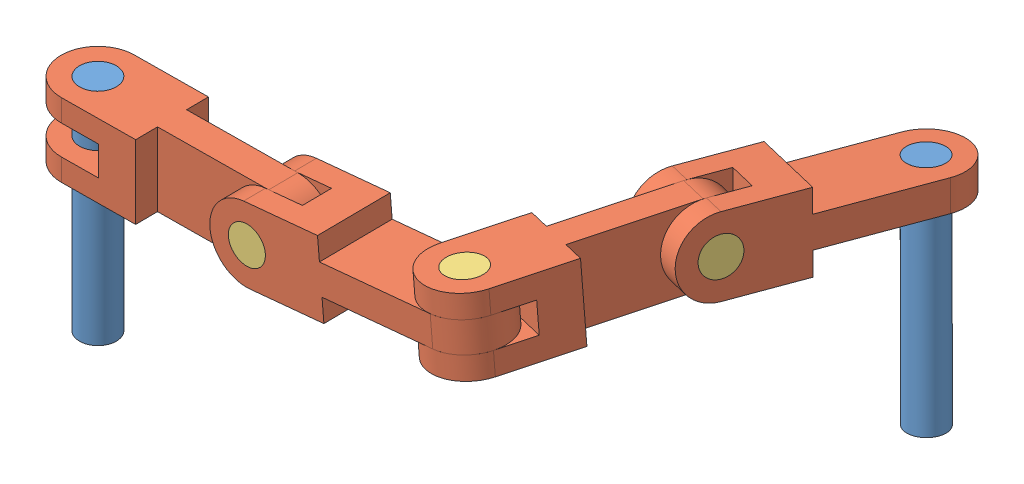
SolidWorks assembly Yucra_Fabrizio_E01, configuration Predeterminado. Lengths in mm.
Overall size (761.39 348.45 605.76).
9 component instances, 3 part files, 17 mates.
Components (placement in the parent):
- Yucra_Fabrizio_P53B-1: Yucra_Fabrizio_P53B [Predeterminado] at (137.0734 -21.0496 253.5842) size (50 300 50)
- Yucra_Fabrizio_P53A-5: Yucra_Fabrizio_P53A [Predeterminado] at (237.069 228.9504 252.6406) x (0.009436 0 0.999955) z (0 -1 0) size (100 350 100)
- Yucra_Fabrizio_P53C-1: Yucra_Fabrizio_P53C [Predeterminado] at (387.5341 228.9504 301.223) x (-0.399413 0.916763 0.003769) z (-0.916723 -0.399431 0.008651) size (50 100 50)
- Yucra_Fabrizio_P53A-6: Yucra_Fabrizio_P53A [Predeterminado] at (486.6837 237.5928 250.2852) x (-0.08642 0.996258 0.000815) z (0.009436 0 0.999955) size (100 350 100)
- Yucra_Fabrizio_P53C-2: Yucra_Fabrizio_P53C [Predeterminado] at (640.4368 200.7434 248.8343) x (-0.954646 -0.083044 0.285928) z (-0.284926 -0.023931 -0.958251) size (50 100 50)
- Yucra_Fabrizio_P53A-7: Yucra_Fabrizio_P53A [Predeterminado] at (665.0846 253.1475 153.198) x (-0.953212 -0.082447 -0.290844) z (-0.08642 0.996258 0.000815) size (100 350 100)
- Yucra_Fabrizio_P53C-3: Yucra_Fabrizio_P53C [Predeterminado] at (660.8773 252.9119 -4.8597) x (0.280824 -0.597674 -0.750948) z (-0.111916 -0.797488 0.592863) size (50 100 50)
- Yucra_Fabrizio_P53A-8: Yucra_Fabrizio_P53A [Predeterminado] at (738.0292 252.8163 -85.7768) x (-0.066436 0.995702 -0.064521) z (0.953212 0.082447 0.290844) size (100 350 100)
- Yucra_Fabrizio_P53B-2: Yucra_Fabrizio_P53B [Predeterminado] at (800.8682 -32.3074 -210.8997) x (0.33698 0.083255 0.937823) z (-0.939165 -0.040563 0.341063) size (50 300 50)
Mates (geometry in assembly coordinates):
- Concéntrica2: concentric anti-aligned: cylinder of Yucra_Fabrizio_P53B-1 through (137.0734 278.9504 253.5842) axis (0 -1 0) radius 25; cylinder of Yucra_Fabrizio_P53A-5 through (137.0734 178.9504 253.5842) axis (0 1 0) radius 25
- Ancho2: width aligned: plane of Yucra_Fabrizio_P53B-1 through (137.0734 278.9504 253.5842) normal (0 1 0); plane of Yucra_Fabrizio_P53B-1 through (137.0734 -21.0496 253.5842) normal (0 -1 0); plane of Yucra_Fabrizio_P53A-5 through (137.0734 278.9504 253.5842) normal (0 1 0); plane of Yucra_Fabrizio_P53A-5 through (137.0734 178.9504 253.5842) normal (0 -1 0)
- Concéntrica3: concentric anti-aligned: cylinder of Yucra_Fabrizio_P53A-5 through (387.251 228.9504 271.2243) axis (-0.009436 0 -0.999955) radius 25; cylinder of Yucra_Fabrizio_P53C-1 through (386.5905 228.9504 201.2275) axis (0.009436 0 0.999955) radius 25
- Concéntrica4: concentric anti-aligned: cylinder of Yucra_Fabrizio_P53C-1 through (386.5905 228.9504 201.2275) axis (0.009436 0 0.999955) radius 25; cylinder of Yucra_Fabrizio_P53A-6 through (387.5341 228.9504 301.223) axis (-0.009436 0 -0.999955) radius 25
- Ancho3: width anti-aligned: plane of Yucra_Fabrizio_P53C-1 through (386.5905 228.9504 201.2275) normal (-0.009436 0 -0.999955); plane of Yucra_Fabrizio_P53C-1 through (387.5341 228.9504 301.223) normal (0.009436 0 0.999955); plane of Yucra_Fabrizio_P53A-5 through (387.251 228.9504 271.2243) normal (0.009436 0 0.999955); plane of Yucra_Fabrizio_P53A-5 through (386.8736 228.9504 231.2261) normal (-0.009436 0 -0.999955)
- Coincidente2: coincident aligned: plane of Yucra_Fabrizio_P53C-1 through (387.5341 228.9504 301.223) normal (0.009436 0 0.999955); plane of Yucra_Fabrizio_P53A-6 through (387.5341 228.9504 301.223) normal (0.009436 0 0.999955)
- Concéntrica5: concentric aligned: cylinder of Yucra_Fabrizio_P53A-6 through (634.3874 270.4814 248.8914) axis (0.08642 -0.996258 -0.000815) radius 25; cylinder of Yucra_Fabrizio_P53C-2 through (631.7948 300.3692 248.9158) axis (0.08642 -0.996258 -0.000815) radius 25
- Ancho4: width aligned: plane of Yucra_Fabrizio_P53C-2 through (631.7948 300.3692 248.9158) normal (-0.08642 0.996258 0.000815); plane of Yucra_Fabrizio_P53A-6 through (640.4368 200.7434 248.8343) normal (0.08642 -0.996258 -0.000815); plane of Yucra_Fabrizio_P53C-2 through (634.3874 270.4814 248.8914) normal (-0.08642 0.996258 0.000815); plane of Yucra_Fabrizio_P53A-6 through (637.8442 230.6311 248.8588) normal (0.08642 -0.996258 -0.000815)
- Concéntrica6: concentric aligned: cylinder of Yucra_Fabrizio_P53C-2 through (631.7948 300.3692 248.9158) axis (0.08642 -0.996258 -0.000815) radius 25; cylinder of Yucra_Fabrizio_P53A-7 through (631.7948 300.3692 248.9158) axis (0.08642 -0.996258 -0.000815) radius 25
- Coincidente3: coincident aligned: plane of Yucra_Fabrizio_P53C-2 through (631.7948 300.3692 248.9158) normal (-0.08642 0.996258 0.000815); plane of Yucra_Fabrizio_P53A-7 through (631.7948 300.3692 248.9158) normal (-0.08642 0.996258 0.000815)
- Coincidente4: coincident aligned: plane of Yucra_Fabrizio_P53B-1 through (137.0734 278.9504 253.5842) normal (0 1 0); plane of Yucra_Fabrizio_P53A-5 through (137.0734 278.9504 253.5842) normal (0 1 0)
- Concéntrica7: concentric anti-aligned: cylinder of Yucra_Fabrizio_P53A-7 through (689.4736 255.3853 3.8656) axis (0.953212 0.082447 0.290844) radius 25; cylinder of Yucra_Fabrizio_P53C-3 through (756.1984 261.1566 24.2247) axis (-0.953212 -0.082447 -0.290844) radius 25
- Ancho5: width aligned: plane of Yucra_Fabrizio_P53C-3 through (756.1984 261.1566 24.2247) normal (0.953212 0.082447 0.290844); plane of Yucra_Fabrizio_P53A-7 through (660.8773 252.9119 -4.8597) normal (-0.953212 -0.082447 -0.290844); plane of Yucra_Fabrizio_P53C-3 through (727.6021 258.6832 15.4994) normal (0.953212 0.082447 0.290844); plane of Yucra_Fabrizio_P53A-7 through (689.4736 255.3853 3.8656) normal (-0.953212 -0.082447 -0.290844)
- Concéntrica8: concentric aligned: cylinder of Yucra_Fabrizio_P53C-3 through (756.1984 261.1566 24.2247) axis (-0.953212 -0.082447 -0.290844) radius 25; cylinder of Yucra_Fabrizio_P53A-8 through (756.1984 261.1566 24.2247) axis (-0.953212 -0.082447 -0.290844) radius 25
- Coincidente5: coincident aligned: plane of Yucra_Fabrizio_P53C-3 through (756.1984 261.1566 24.2247) normal (0.953212 0.082447 0.290844); plane of Yucra_Fabrizio_P53A-8 through (756.1984 261.1566 24.2247) normal (0.953212 0.082447 0.290844)
- Concéntrica9: concentric aligned: cylinder of Yucra_Fabrizio_P53A-8 through (780.9374 266.4033 -230.2561) axis (0.066436 -0.995702 0.064521) radius 25; cylinder of Yucra_Fabrizio_P53B-2 through (780.9374 266.4033 -230.2561) axis (0.066436 -0.995702 0.064521) radius 25
- Coincidente6: coincident aligned: plane of Yucra_Fabrizio_P53A-8 through (780.9374 266.4033 -230.2561) normal (-0.066436 0.995702 -0.064521); plane of Yucra_Fabrizio_P53B-2 through (780.9374 266.4033 -230.2561) normal (-0.066436 0.995702 -0.064521)
